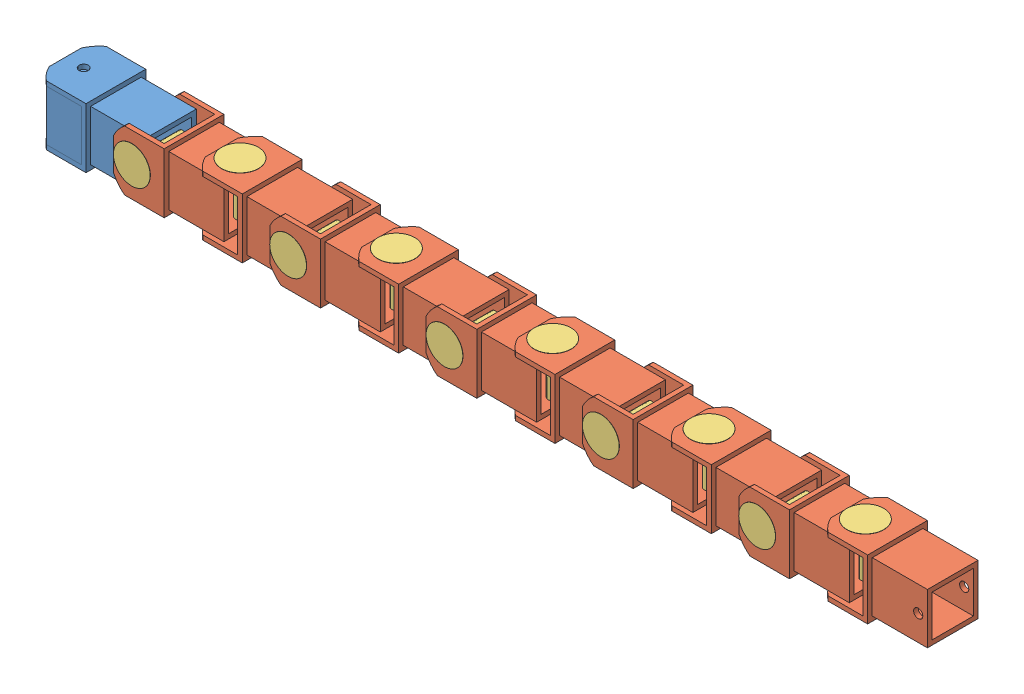
SolidWorks assembly new, configuration Default. Lengths in mm.
Overall size (2451.1 166.12 166.12).
21 component instances, 3 part files, 40 mates.
Components (placement in the parent):
- head-1: head [Default] at origin size (292.1 165.1 165.1)
- link-1: link [Default] at (215.9 0.0003 0.0003) size (292.1 165.1 165.1)
- link-2: link [Default] at (431.8 31.7503 31.7503) x (1 0 0) z (0 -1 0) size (292.1 165.1 165.1)
- link-3: link [Default] at (647.7 0.0003 0.0003) size (292.1 165.1 165.1)
- link-4: link [Default] at (863.6 31.7503 31.7503) x (1 0 0) z (0 -1 0) size (292.1 165.1 165.1)
- link-5: link [Default] at (1079.5 0.0003 0.0003) size (292.1 165.1 165.1)
- link-6: link [Default] at (1295.4 31.7503 31.7503) x (1 0 0) z (0 -1 0) size (292.1 165.1 165.1)
- link-7: link [Default] at (1511.3 0.0003 0.0003) size (292.1 165.1 165.1)
- link-8: link [Default] at (1727.2 31.7503 31.7503) x (1 0 0) z (0 -1 0) size (292.1 165.1 165.1)
- link-9: link [Default] at (1943.1 0.0003 0.0003) size (292.1 165.1 165.1)
- link-10: link [Default] at (2159 31.7503 31.7503) x (1 0 0) z (0 -1 0) size (292.1 165.1 165.1)
- rod-1: rod [Default] at (215.9 0.0003 31.7503) x (1 0 0) z (0 -1 0) size (101.6 166.12 101.6)
- rod-3: rod [Default] at (431.8 0.0003 31.7503) size (101.6 166.12 101.6)
- rod-4: rod [Default] at (647.7 0.0003 31.7503) x (0.999109 -0.042195 0) z (-0.042195 -0.999109 0) size (101.6 166.12 101.6)
- rod-5: rod [Default] at (863.6 0.0003 31.7503) size (101.6 166.12 101.6)
- rod-6: rod [Default] at (1079.5 0.0003 31.7503) x (1 0 0) z (0 -1 0) size (101.6 166.12 101.6)
- rod-7: rod [Default] at (1295.4 0.0003 31.7503) size (101.6 166.12 101.6)
- rod-8: rod [Default] at (1511.3 0.0003 31.7503) x (1 0 0) z (0 -1 0) size (101.6 166.12 101.6)
- rod-9: rod [Default] at (1727.2 0.0003 31.7503) size (101.6 166.12 101.6)
- rod-10: rod [Default] at (1943.1 0.0003 31.7503) x (1 0 0) z (0 -1 0) size (101.6 166.12 101.6)
- rod-11: rod [Default] at (2159 0.0003 31.7503) size (101.6 166.12 101.6)
Mates (geometry in assembly coordinates):
- Concentric1: concentric aligned: cylinder of head-1 through (215.9 0.0003 -50.7997) axis (0 0 1) radius 12.7; cylinder of link-1 through (215.9 0.0003 -50.7997) axis (0 0 1) radius 12.7
- Coincident1: coincident anti-aligned: plane of head-1 through (241.3 -69.8498 101.6003) normal (0 0 1); plane of link-1 through (292.1 82.5503 101.6003) normal (0 0 -1)
- Concentric2: concentric anti-aligned: cylinder of link-1 through (431.8 -82.5498 31.7503) axis (0 1 0) radius 12.7; cylinder of link-2 through (431.8 82.5503 31.7503) axis (0 -1 0) radius 12.7
- Coincident2: coincident anti-aligned: plane of link-1 through (457.2 -69.8498 101.6003) normal (0 -1 0); plane of link-2 through (508 -69.8498 114.3003) normal (0 1 0)
- Concentric4: concentric aligned: cylinder of link-2 through (647.7 0.0003 -50.7997) axis (0 0 1) radius 12.7; cylinder of link-3 through (647.7 0.0003 -50.7997) axis (0 0 1) radius 12.7
- Coincident3: coincident anti-aligned: plane of link-2 through (673.1 -69.8498 -38.0998) normal (0 0 -1); plane of link-3 through (596.9 82.5503 -38.0998) normal (0 0 1)
- Concentric5: concentric anti-aligned: cylinder of link-3 through (863.6 -82.5498 31.7503) axis (0 1 0) radius 12.7; cylinder of link-4 through (863.6 82.5503 31.7503) axis (0 -1 0) radius 12.7
- Coincident4: coincident anti-aligned: plane of link-3 through (889 -69.8498 101.6003) normal (0 -1 0); plane of link-4 through (939.8 -69.8498 114.3003) normal (0 1 0)
- Concentric6: concentric aligned: cylinder of link-4 through (1079.5 0.0003 -50.7997) axis (0 0 1) radius 12.7; cylinder of link-5 through (1079.5 0.0003 -50.7997) axis (0 0 1) radius 12.7
- Coincident5: coincident anti-aligned: plane of link-4 through (1104.9 -69.8498 -38.0998) normal (0 0 -1); plane of link-5 through (1028.7 82.5503 -38.0998) normal (0 0 1)
- Concentric7: concentric anti-aligned: cylinder of link-5 through (1295.4 -82.5498 31.7503) axis (0 1 0) radius 12.7; cylinder of link-6 through (1295.4 82.5503 31.7503) axis (0 -1 0) radius 12.7
- Coincident6: coincident anti-aligned: plane of link-5 through (1320.8 -69.8498 101.6003) normal (0 -1 0); plane of link-6 through (1371.6 -69.8498 114.3003) normal (0 1 0)
- Concentric9: concentric aligned: cylinder of link-6 through (1511.3 0.0003 -50.7997) axis (0 0 1) radius 12.7; cylinder of link-7 through (1511.3 0.0003 -50.7997) axis (0 0 1) radius 12.7
- Coincident8: coincident anti-aligned: plane of link-6 through (1536.7 -69.8498 -38.0998) normal (0 0 -1); plane of link-7 through (1460.5 82.5503 -38.0998) normal (0 0 1)
- Concentric10: concentric anti-aligned: cylinder of link-7 through (1727.2 -82.5498 31.7503) axis (0 1 0) radius 12.7; cylinder of link-8 through (1727.2 82.5503 31.7503) axis (0 -1 0) radius 12.7
- Coincident9: coincident anti-aligned: plane of link-7 through (1752.6 -69.8498 101.6003) normal (0 -1 0); plane of link-8 through (1803.4 -69.8498 114.3003) normal (0 1 0)
- Concentric11: concentric aligned: cylinder of link-8 through (1943.1 0.0003 -50.7997) axis (0 0 1) radius 12.7; cylinder of link-9 through (1943.1 0.0003 -50.7997) axis (0 0 1) radius 12.7
- Coincident10: coincident anti-aligned: plane of link-8 through (1968.5 -69.8498 -38.0998) normal (0 0 -1); plane of link-9 through (1892.3 82.5503 -38.0998) normal (0 0 1)
- Concentric12: concentric anti-aligned: cylinder of link-9 through (2159 -82.5498 31.7503) axis (0 1 0) radius 12.7; cylinder of link-10 through (2159 82.5503 31.7503) axis (0 -1 0) radius 12.7
- Coincident11: coincident anti-aligned: plane of link-9 through (2184.4 -69.8498 101.6003) normal (0 -1 0); plane of link-10 through (2235.2 -69.8498 114.3003) normal (0 1 0)
- Concentric13: concentric anti-aligned: cylinder of link-1 through (215.9 0.0003 -50.7997) axis (0 0 1) radius 12.7; cylinder of rod-1 through (215.9 0.0003 114.8083) axis (0 0 -1) radius 50.8
- Coincident12: coincident anti-aligned: plane of link-1 through (304.8 82.5503 -50.7997) normal (0 0 -1); plane of rod-1 through (215.9 0.0003 -50.7997) normal (0 0 1)
- Concentric15: concentric aligned: cylinder of link-2 through (431.8 82.5503 31.7503) axis (0 -1 0) radius 12.7; cylinder of rod-3 through (431.8 83.0583 31.7503) axis (0 -1 0) radius 50.8
- Coincident13: coincident anti-aligned: plane of link-2 through (381 -82.5498 114.3003) normal (0 -1 0); plane of rod-3 through (431.8 -82.5498 31.7503) normal (0 1 0)
- Concentric16: concentric anti-aligned: cylinder of link-3 through (647.7 0.0003 -50.7997) axis (0 0 1) radius 12.7; cylinder of rod-4 through (647.7 0.0003 114.8083) axis (0 0 -1) radius 50.8
- Coincident14: coincident anti-aligned: plane of link-3 through (596.9 82.5503 114.3003) normal (0 0 1); plane of rod-4 through (647.7 0.0003 114.3003) normal (0 0 -1)
- Concentric17: concentric aligned: cylinder of link-4 through (863.6 82.5503 31.7503) axis (0 -1 0) radius 12.7; cylinder of rod-5 through (863.6 83.0583 31.7503) axis (0 -1 0) radius 50.8
- Coincident15: coincident anti-aligned: plane of link-4 through (812.8 -82.5498 114.3003) normal (0 -1 0); plane of rod-5 through (863.6 -82.5498 31.7503) normal (0 1 0)
- Concentric18: concentric anti-aligned: cylinder of link-5 through (1079.5 0.0003 -50.7997) axis (0 0 1) radius 12.7; cylinder of rod-6 through (1079.5 0.0003 114.8083) axis (0 0 -1) radius 50.8
- Coincident16: coincident anti-aligned: plane of link-5 through (1168.4 82.5503 -50.7997) normal (0 0 -1); plane of rod-6 through (1079.5 0.0003 -50.7997) normal (0 0 1)
- Concentric19: concentric aligned: cylinder of link-6 through (1295.4 82.5503 31.7503) axis (0 -1 0) radius 12.7; cylinder of rod-7 through (1295.4 83.0583 31.7503) axis (0 -1 0) radius 50.8
- Coincident17: coincident anti-aligned: plane of link-6 through (1384.3 82.5503 114.3003) normal (0 1 0); plane of rod-7 through (1295.4 82.5503 31.7503) normal (0 -1 0)
- Concentric20: concentric anti-aligned: cylinder of link-7 through (1511.3 0.0003 -50.7997) axis (0 0 1) radius 12.7; cylinder of rod-8 through (1511.3 0.0003 114.8083) axis (0 0 -1) radius 50.8
- Coincident18: coincident anti-aligned: plane of link-7 through (1460.5 82.5503 114.3003) normal (0 0 1); plane of rod-8 through (1511.3 0.0003 114.3003) normal (0 0 -1)
- Concentric21: concentric aligned: cylinder of link-8 through (1727.2 82.5503 31.7503) axis (0 -1 0) radius 12.7; cylinder of rod-9 through (1727.2 83.0583 31.7503) axis (0 -1 0) radius 50.8
- Coincident19: coincident aligned: plane of link-8 through (1816.1 82.5503 114.3003) normal (0 1 0); circle of rod-9
- Concentric22: concentric anti-aligned: cylinder of link-9 through (1943.1 0.0003 -50.7997) axis (0 0 1) radius 12.7; cylinder of rod-10 through (1943.1 0.0003 114.8083) axis (0 0 -1) radius 50.8
- Coincident20: coincident anti-aligned: plane of link-9 through (1892.3 82.5503 114.3003) normal (0 0 1); plane of rod-10 through (1943.1 0.0003 114.3003) normal (0 0 -1)
- Concentric25: concentric aligned: cylinder of link-10 through (2159 82.5503 31.7503) axis (0 -1 0) radius 12.7; cylinder of rod-11 through (2159 83.0583 31.7503) axis (0 -1 0) radius 50.8
- Coincident21: coincident anti-aligned: plane of link-10 through (2247.9 82.5503 114.3003) normal (0 1 0); plane of rod-11 through (2159 82.5503 31.7503) normal (0 -1 0)
